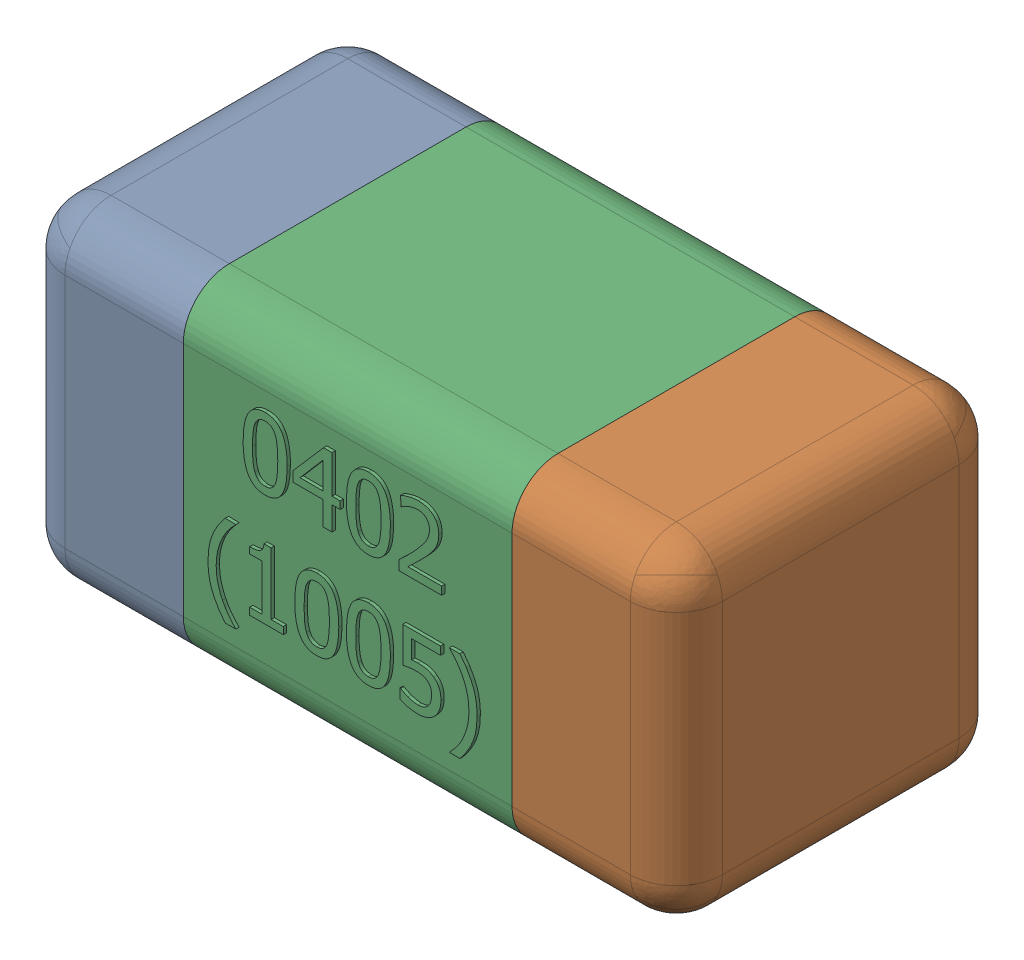
SolidWorks assembly C11, configuration Standard. Lengths in mm.
Overall size (1.01 0.51 0.51).
4 component instances, 3 part files, 0 mates.
Components (placement in the parent):
- C11-subassembly-1-1: C11-subassembly-1 [Standard] at (8.6001 -15.8 0) x (1 0 0) z (0 0 1) size (1.01 0.51 0.51)
  - User Library-0402_Cap-1: User Library-0402_Cap [Standard] at origin size (0.26 0.51 0.51)
  - User Library-0402_Cap-1-1: User Library-0402_Cap-1 [Standard] at origin size (0.26 0.5 0.51)
  - User Library-0402_Cap-2-1: User Library-0402_Cap-2 [Standard] at origin size (0.5 0.5 0.51)
